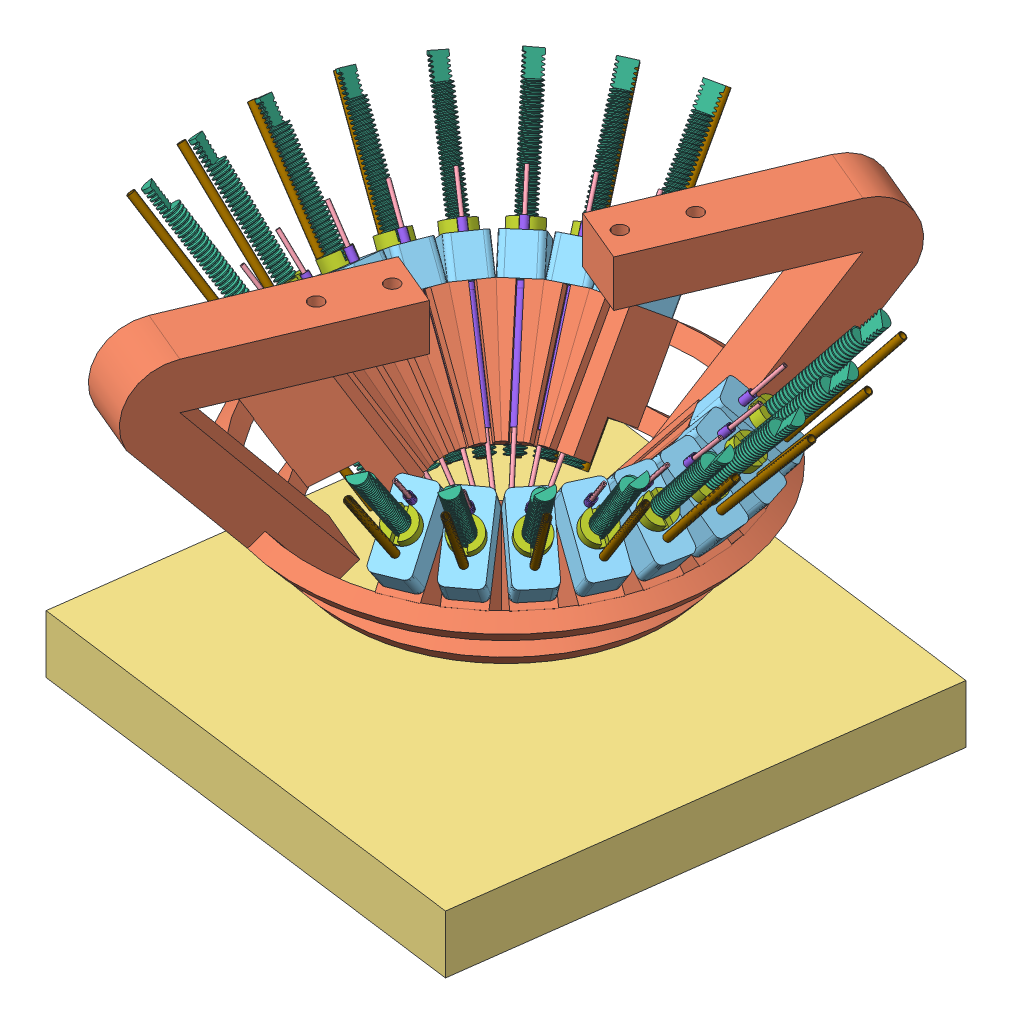
SolidWorks assembly DriveAssembling_Step4, configuration Default. Lengths in mm.
Overall size (53.46 35.24 53.46).
115 component instances, 9 part files, 84 mates.
Components (placement in the parent):
- MainCanula-1: MainCanula [Default] at (-0.6109 2 -0.3095) size (2.41 8 2.41)
- drive_circle_16-1: drive_circle_16 [Default] at (-0.6109 7.8932 -0.3095) x (0.377897 0 0.925848) z (-0.925848 0 0.377897) size (41.01 26.14 41.01)
- SingleCanulaBase-1: SingleCanulaBase [Default] at (-0.6109 0 -0.3095) x (0.991445 0 0.130526) z (-0.130526 0 0.991445) size (40 5 40)
- 30g_curved_long-18: 30g_curved_long [Default] at (-0.577 8 -0.2265) x (0.377897 0 0.925848) z (-0.925848 0 0.377897) size (17.44 28.79 0.32)
- ShuttleAssembly-1: ShuttleAssembly [Default] at (-0.0983 18.931 15.5592) x (-0.289486 0.642788 -0.70924) z (0.925848 0 -0.377897) size (6.5 25.22 3)
  - drive_shuttle-1: drive_shuttle [Default] at (2.5582 1.9761 5.5221) size (6.5 3 3)
  - drive_threaded_rod_25mm-1: drive_threaded_rod_25mm [Default] at (2.5582 -8.5786 5.5221) x (0.813094 0 0.582132) z (-0.582132 0 0.813094) size (1.64 25.22 1.64)
  - Grooved Nut-1: Grooved Nut [Default] at (2.5582 1.9761 5.5221) size (2.5 4 2.5)
  - guide_23g_13mm-1: guide_23g_13mm [Default] at (4.3082 -7.0239 5.5221) size (0.64 13 0.64)
  - stabilizer_23g_25mm-1: stabilizer_23g_25mm [Default] at (0.8082 -8.5786 5.5221) size (0.62 25 0.62)
- 30g_curved_long-23: 30g_curved_long [Default] at (-0.5576 8 -0.2375) x (0.594671 0 0.803969) z (-0.803969 0 0.594671) size (17.44 28.79 0.32)
- ShuttleAssembly-6: ShuttleAssembly [Default] at (3.8016 18.931 14.942) x (-0.455545 0.642788 -0.615876) z (0.803969 0 -0.594671) size (6.5 25.22 3)
  - drive_shuttle-1: drive_shuttle [Default] at (2.5582 1.9761 5.5221) size (6.5 3 3)
  - drive_threaded_rod_25mm-1: drive_threaded_rod_25mm [Default] at (2.5582 -8.5786 5.5221) x (0.813094 0 0.582132) z (-0.582132 0 0.813094) size (1.64 25.22 1.64)
  - Grooved Nut-1: Grooved Nut [Default] at (2.5582 1.9761 5.5221) size (2.5 4 2.5)
  - guide_23g_13mm-1: guide_23g_13mm [Default] at (4.3082 -7.0239 5.5221) size (0.64 13 0.64)
  - stabilizer_23g_25mm-1: stabilizer_23g_25mm [Default] at (0.8082 -8.5786 5.5221) size (0.62 25 0.62)
- 30g_curved_long-24: 30g_curved_long [Default] at (-0.5414 8 -0.2528) x (0.774668 0 0.632368) z (-0.632368 0 0.774668) size (17.44 28.79 0.32)
- ShuttleAssembly-7: ShuttleAssembly [Default] at (7.4286 18.931 13.3816) x (-0.59343 0.642788 -0.484422) z (0.632368 0 -0.774668) size (6.5 25.22 3)
  - drive_shuttle-1: drive_shuttle [Default] at (2.5582 1.9761 5.5221) size (6.5 3 3)
  - drive_threaded_rod_25mm-1: drive_threaded_rod_25mm [Default] at (2.5582 -8.5786 5.5221) x (0.813094 0 0.582132) z (-0.582132 0 0.813094) size (1.64 25.22 1.64)
  - Grooved Nut-1: Grooved Nut [Default] at (2.5582 1.9761 5.5221) size (2.5 4 2.5)
  - guide_23g_13mm-1: guide_23g_13mm [Default] at (4.3082 -7.0239 5.5221) size (0.64 13 0.64)
  - stabilizer_23g_25mm-1: stabilizer_23g_25mm [Default] at (0.8082 -8.5786 5.5221) size (0.62 25 0.62)
- 30g_curved_long-26: 30g_curved_long [Default] at (-0.5296 8 -0.2717) x (0.906755 0 0.421659) z (-0.421659 0 0.906755) size (17.44 28.79 0.32)
- ShuttleAssembly-9: ShuttleAssembly [Default] at (10.5584 18.931 10.9744) x (-0.694614 0.642788 -0.323009) z (0.421659 0 -0.906755) size (6.5 25.22 3)
  - drive_shuttle-1: drive_shuttle [Default] at (2.5582 1.9761 5.5221) size (6.5 3 3)
  - drive_threaded_rod_25mm-1: drive_threaded_rod_25mm [Default] at (2.5582 -8.5786 5.5221) x (0.813094 0 0.582132) z (-0.582132 0 0.813094) size (1.64 25.22 1.64)
  - Grooved Nut-1: Grooved Nut [Default] at (2.5582 1.9761 5.5221) size (2.5 4 2.5)
  - guide_23g_13mm-1: guide_23g_13mm [Default] at (4.3082 -7.0239 5.5221) size (0.64 13 0.64)
  - stabilizer_23g_25mm-1: stabilizer_23g_25mm [Default] at (0.8082 -8.5786 5.5221) size (0.62 25 0.62)
- 30g_curved_long-27: 30g_curved_long [Default] at (-0.5228 8 -0.293) x (0.982763 0 0.184872) z (-0.184872 0 0.982763) size (17.44 28.79 0.32)
- ShuttleAssembly-10: ShuttleAssembly [Default] at (12.9974 18.931 7.8694) x (-0.75284 0.642788 -0.14162) z (0.184872 0 -0.982763) size (6.5 25.22 3)
  - drive_shuttle-1: drive_shuttle [Default] at (2.5582 1.9761 5.5221) size (6.5 3 3)
  - drive_threaded_rod_25mm-1: drive_threaded_rod_25mm [Default] at (2.5582 -8.5786 5.5221) x (0.813094 0 0.582132) z (-0.582132 0 0.813094) size (1.64 25.22 1.64)
  - Grooved Nut-1: Grooved Nut [Default] at (2.5582 1.9761 5.5221) size (2.5 4 2.5)
  - guide_23g_13mm-1: guide_23g_13mm [Default] at (4.3082 -7.0239 5.5221) size (0.64 13 0.64)
  - stabilizer_23g_25mm-1: stabilizer_23g_25mm [Default] at (0.8082 -8.5786 5.5221) size (0.62 25 0.62)
- 30g_curved_long-28: 30g_curved_long [Default] at (-0.5214 8 -0.3152) x (0.997991 0 -0.063349) z (0.063349 0 0.997991) size (17.44 28.79 0.32)
- ShuttleAssembly-11: ShuttleAssembly [Default] at (14.5948 18.931 4.2585) x (-0.764506 0.642788 0.048528) z (-0.063349 0 -0.997991) size (6.5 25.22 3)
  - drive_shuttle-1: drive_shuttle [Default] at (2.5582 1.9761 5.5221) size (6.5 3 3)
  - drive_threaded_rod_25mm-1: drive_threaded_rod_25mm [Default] at (2.5582 -8.5786 5.5221) x (0.813094 0 0.582132) z (-0.582132 0 0.813094) size (1.64 25.22 1.64)
  - Grooved Nut-1: Grooved Nut [Default] at (2.5582 1.9761 5.5221) size (2.5 4 2.5)
  - guide_23g_13mm-1: guide_23g_13mm [Default] at (4.3082 -7.0239 5.5221) size (0.64 13 0.64)
  - stabilizer_23g_25mm-1: stabilizer_23g_25mm [Default] at (0.8082 -8.5786 5.5221) size (0.62 25 0.62)
- 30g_curved_long-29: 30g_curved_long [Default] at (-0.5256 8 -0.3371) x (0.951499 0 -0.307652) z (0.307652 0 0.951499) size (17.44 28.79 0.32)
- ShuttleAssembly-12: ShuttleAssembly [Default] at (15.2518 18.931 0.3651) x (-0.728891 0.642788 0.235675) z (-0.307652 0 -0.951499) size (6.5 25.22 3)
  - drive_shuttle-1: drive_shuttle [Default] at (2.5582 1.9761 5.5221) size (6.5 3 3)
  - drive_threaded_rod_25mm-1: drive_threaded_rod_25mm [Default] at (2.5582 -8.5786 5.5221) x (0.813094 0 0.582132) z (-0.582132 0 0.813094) size (1.64 25.22 1.64)
  - Grooved Nut-1: Grooved Nut [Default] at (2.5582 1.9761 5.5221) size (2.5 4 2.5)
  - guide_23g_13mm-1: guide_23g_13mm [Default] at (4.3082 -7.0239 5.5221) size (0.64 13 0.64)
  - stabilizer_23g_25mm-1: stabilizer_23g_25mm [Default] at (0.8082 -8.5786 5.5221) size (0.62 25 0.62)
- 30g_curved_long-30: 30g_curved_long [Default] at (-0.535 8 -0.3573) x (0.846161 0 -0.532928) z (0.532928 0 0.846161) size (17.44 28.79 0.32)
- ShuttleAssembly-13: ShuttleAssembly [Default] at (14.9278 18.931 -3.5699) x (-0.648197 0.642788 0.408246) z (-0.532928 0 -0.846161) size (6.5 25.22 3)
  - drive_shuttle-1: drive_shuttle [Default] at (2.5582 1.9761 5.5221) size (6.5 3 3)
  - drive_threaded_rod_25mm-1: drive_threaded_rod_25mm [Default] at (2.5582 -8.5786 5.5221) x (0.813094 0 0.582132) z (-0.582132 0 0.813094) size (1.64 25.22 1.64)
  - Grooved Nut-1: Grooved Nut [Default] at (2.5582 1.9761 5.5221) size (2.5 4 2.5)
  - guide_23g_13mm-1: guide_23g_13mm [Default] at (4.3082 -7.0239 5.5221) size (0.64 13 0.64)
  - stabilizer_23g_25mm-1: stabilizer_23g_25mm [Default] at (0.8082 -8.5786 5.5221) size (0.62 25 0.62)
- 30g_curved_long-42: 30g_curved_long [Default] at (-0.6298 8 -0.3972) x (-0.211384 0 -0.977403) z (0.977403 0 -0.211384) size (17.44 28.79 0.32)
- ShuttleAssembly-25: ShuttleAssembly [Default] at (1.6399 18.931 -16.0262) x (0.16193 0.642788 0.748734) z (-0.977403 0 0.211384) size (6.5 25.22 3)
  - drive_shuttle-1: drive_shuttle [Default] at (2.5582 1.9761 5.5221) size (6.5 3 3)
  - drive_threaded_rod_25mm-1: drive_threaded_rod_25mm [Default] at (2.5582 -8.5786 5.5221) x (0.813094 0 0.582132) z (-0.582132 0 0.813094) size (1.64 25.22 1.64)
  - Grooved Nut-1: Grooved Nut [Default] at (2.5582 1.9761 5.5221) size (2.5 4 2.5)
  - guide_23g_13mm-1: guide_23g_13mm [Default] at (4.3082 -7.0239 5.5221) size (0.64 13 0.64)
  - stabilizer_23g_25mm-1: stabilizer_23g_25mm [Default] at (0.8082 -8.5786 5.5221) size (0.62 25 0.62)
- 30g_curved_long-43: 30g_curved_long [Default] at (-0.6509 8 -0.3898) x (-0.446029 0 -0.895018) z (0.895018 0 -0.446029) size (17.44 28.79 0.32)
- ShuttleAssembly-26: ShuttleAssembly [Default] at (-2.3079 18.931 -16.0956) x (0.341678 0.642788 0.685624) z (-0.895018 0 0.446029) size (6.5 25.22 3)
  - drive_shuttle-1: drive_shuttle [Default] at (2.5582 1.9761 5.5221) size (6.5 3 3)
  - drive_threaded_rod_25mm-1: drive_threaded_rod_25mm [Default] at (2.5582 -8.5786 5.5221) x (0.813094 0 0.582132) z (-0.582132 0 0.813094) size (1.64 25.22 1.64)
  - Grooved Nut-1: Grooved Nut [Default] at (2.5582 1.9761 5.5221) size (2.5 4 2.5)
  - guide_23g_13mm-1: guide_23g_13mm [Default] at (4.3082 -7.0239 5.5221) size (0.64 13 0.64)
  - stabilizer_23g_25mm-1: stabilizer_23g_25mm [Default] at (0.8082 -8.5786 5.5221) size (0.62 25 0.62)
- 30g_curved_long-44: 30g_curved_long [Default] at (-0.6694 8 -0.3774) x (-0.653089 0 -0.757281) z (0.757281 0 -0.653089) size (17.44 28.79 0.32)
- ShuttleAssembly-27: ShuttleAssembly [Default] at (-6.1508 18.931 -15.1887) x (0.500295 0.642788 0.580111) z (-0.757281 0 0.653089) size (6.5 25.22 3)
  - drive_shuttle-1: drive_shuttle [Default] at (2.5582 1.9761 5.5221) size (6.5 3 3)
  - drive_threaded_rod_25mm-1: drive_threaded_rod_25mm [Default] at (2.5582 -8.5786 5.5221) x (0.813094 0 0.582132) z (-0.582132 0 0.813094) size (1.64 25.22 1.64)
  - Grooved Nut-1: Grooved Nut [Default] at (2.5582 1.9761 5.5221) size (2.5 4 2.5)
  - guide_23g_13mm-1: guide_23g_13mm [Default] at (4.3082 -7.0239 5.5221) size (0.64 13 0.64)
  - stabilizer_23g_25mm-1: stabilizer_23g_25mm [Default] at (0.8082 -8.5786 5.5221) size (0.62 25 0.62)
- 30g_curved_long-45: 30g_curved_long [Default] at (-0.6844 8 -0.3609) x (-0.819759 0 -0.572709) z (0.572709 0 -0.819759) size (17.44 28.79 0.32)
- ShuttleAssembly-28: ShuttleAssembly [Default] at (-9.651 18.931 -13.3616) x (0.627971 0.642788 0.438721) z (-0.572709 0 0.819759) size (6.5 25.22 3)
  - drive_shuttle-1: drive_shuttle [Default] at (2.5582 1.9761 5.5221) size (6.5 3 3)
  - drive_threaded_rod_25mm-1: drive_threaded_rod_25mm [Default] at (2.5582 -8.5786 5.5221) x (0.813094 0 0.582132) z (-0.582132 0 0.813094) size (1.64 25.22 1.64)
  - Grooved Nut-1: Grooved Nut [Default] at (2.5582 1.9761 5.5221) size (2.5 4 2.5)
  - guide_23g_13mm-1: guide_23g_13mm [Default] at (4.3082 -7.0239 5.5221) size (0.64 13 0.64)
  - stabilizer_23g_25mm-1: stabilizer_23g_25mm [Default] at (0.8082 -8.5786 5.5221) size (0.62 25 0.62)
- 30g_curved_long-49: 30g_curved_long [Default] at (-0.6948 8 -0.3412) x (-0.93573 0 -0.352718) z (0.352718 0 -0.93573) size (17.44 28.79 0.32)
- ShuttleAssembly-32: ShuttleAssembly [Default] at (-12.5922 18.931 -10.7272) x (0.716811 0.642788 0.270198) z (-0.352718 0 0.93573) size (6.5 25.22 3)
  - drive_shuttle-1: drive_shuttle [Default] at (2.5582 1.9761 5.5221) size (6.5 3 3)
  - drive_threaded_rod_25mm-1: drive_threaded_rod_25mm [Default] at (2.5582 -8.5786 5.5221) x (0.813094 0 0.582132) z (-0.582132 0 0.813094) size (1.64 25.22 1.64)
  - Grooved Nut-1: Grooved Nut [Default] at (2.5582 1.9761 5.5221) size (2.5 4 2.5)
  - guide_23g_13mm-1: guide_23g_13mm [Default] at (4.3082 -7.0239 5.5221) size (0.64 13 0.64)
  - stabilizer_23g_25mm-1: stabilizer_23g_25mm [Default] at (0.8082 -8.5786 5.5221) size (0.62 25 0.62)
- 30g_curved_long-50: 30g_curved_long [Default] at (-0.7 8 -0.3195) x (-0.99383 0 -0.110913) z (0.110913 0 -0.99383) size (17.44 28.79 0.32)
- ShuttleAssembly-33: ShuttleAssembly [Default] at (-14.7923 18.931 -7.4486) x (0.761318 0.642788 0.084964) z (-0.110913 0 0.99383) size (6.5 25.22 3)
  - drive_shuttle-1: drive_shuttle [Default] at (2.5582 1.9761 5.5221) size (6.5 3 3)
  - drive_threaded_rod_25mm-1: drive_threaded_rod_25mm [Default] at (2.5582 -8.5786 5.5221) x (0.813094 0 0.582132) z (-0.582132 0 0.813094) size (1.64 25.22 1.64)
  - Grooved Nut-1: Grooved Nut [Default] at (2.5582 1.9761 5.5221) size (2.5 4 2.5)
  - guide_23g_13mm-1: guide_23g_13mm [Default] at (4.3082 -7.0239 5.5221) size (0.64 13 0.64)
  - stabilizer_23g_25mm-1: stabilizer_23g_25mm [Default] at (0.8082 -8.5786 5.5221) size (0.62 25 0.62)
- 30g_curved_long-51: 30g_curved_long [Default] at (-0.6997 8 -0.2972) x (-0.990467 0 0.137752) z (-0.137752 0 -0.990467) size (17.44 28.79 0.32)
- ShuttleAssembly-34: ShuttleAssembly [Default] at (-16.1154 18.931 -3.7285) x (0.758742 0.642788 -0.105524) z (0.137752 0 0.990467) size (6.5 25.22 3)
  - drive_shuttle-1: drive_shuttle [Default] at (2.5582 1.9761 5.5221) size (6.5 3 3)
  - drive_threaded_rod_25mm-1: drive_threaded_rod_25mm [Default] at (2.5582 -8.5786 5.5221) x (0.813094 0 0.582132) z (-0.582132 0 0.813094) size (1.64 25.22 1.64)
  - Grooved Nut-1: Grooved Nut [Default] at (2.5582 1.9761 5.5221) size (2.5 4 2.5)
  - guide_23g_13mm-1: guide_23g_13mm [Default] at (4.3082 -7.0239 5.5221) size (0.64 13 0.64)
  - stabilizer_23g_25mm-1: stabilizer_23g_25mm [Default] at (0.8082 -8.5786 5.5221) size (0.62 25 0.62)
- 30g_curved_long-52: 30g_curved_long [Default] at (-0.6939 8 -0.2757) x (-0.925848 0 0.377897) z (-0.377897 0 -0.925848) size (17.44 28.79 0.32)
- ShuttleAssembly-35: ShuttleAssembly [Default] at (-16.4796 18.931 0.2031) x (0.70924 0.642788 -0.289486) z (0.377897 0 0.925848) size (6.5 25.22 3)
  - drive_shuttle-1: drive_shuttle [Default] at (2.5582 1.9761 5.5221) size (6.5 3 3)
  - drive_threaded_rod_25mm-1: drive_threaded_rod_25mm [Default] at (2.5582 -8.5786 5.5221) x (0.813094 0 0.582132) z (-0.582132 0 0.813094) size (1.64 25.22 1.64)
  - Grooved Nut-1: Grooved Nut [Default] at (2.5582 1.9761 5.5221) size (2.5 4 2.5)
  - guide_23g_13mm-1: guide_23g_13mm [Default] at (4.3082 -7.0239 5.5221) size (0.64 13 0.64)
  - stabilizer_23g_25mm-1: stabilizer_23g_25mm [Default] at (0.8082 -8.5786 5.5221) size (0.62 25 0.62)
Mates (geometry in assembly coordinates):
- Concentric3: concentric aligned: circle of MainCanula-1; circle of SingleCanulaBase-1
- Coincident3: coincident aligned: plane of MainCanula-1 through (-0.6109 0 -0.3095) normal (0 -1 0); plane of SingleCanulaBase-1 through (-0.6109 0 -0.3095) normal (0 -1 0)
- Coincident6-30g, bottom: coincident anti-aligned: plane of 30g_curved_long-18 through (-0.5014 0 -0.0414) normal (0 -1 0); plane of assembly through (0 0 0) normal (0 1 0)
- Concentric6-guidetube: concentric aligned: circle of drive_circle_16-1; circle of 30g_curved_long-18
- Concentric7-stabilizer: concentric aligned: circle of drive_circle_16-1; circle of ShuttleAssembly-1/stabilizer_23g_25mm-1
- Concentric8-30g: concentric aligned: circle of 30g_curved_long-18; circle of ShuttleAssembly-1/guide_23g_13mm-1
- Coincident10 - FlushShuttle: coincident anti-aligned: plane of drive_circle_16-1 through (5.2018 24.1782 9.9622) normal (0.242908 0.766044 0.595123); plane of ShuttleAssembly-1/drive_shuttle-1 through (4.7539 22.0892 12.8341) normal (-0.242908 -0.766044 -0.595123)
- Concentric9: concentric anti-aligned: circle of MainCanula-1; circle of drive_circle_16-1
- Concentric20: concentric aligned: circle of 30g_curved_long-23; circle of ShuttleAssembly-6/guide_23g_13mm-1
- Coincident10: coincident anti-aligned: plane of 30g_curved_long-23 through (-0.4386 0 -0.0767) normal (0 -1 0); plane of assembly through (0 0 0) normal (0 1 0)
- Concentric21: concentric aligned: circle of drive_circle_16-1; circle of 30g_curved_long-23
- Concentric22: concentric aligned: circle of drive_circle_16-1; circle of ShuttleAssembly-6/stabilizer_23g_25mm-1
- Coincident11: coincident anti-aligned: plane of drive_circle_16-1 through (7.5567 24.1782 8.2103) normal (0.382247 0.766044 0.516781); plane of ShuttleAssembly-6/drive_shuttle-1 through (7.8313 22.0892 11.1039) normal (-0.382247 -0.766044 -0.516781)
- Concentric23: concentric aligned: circle of 30g_curved_long-24; circle of ShuttleAssembly-7/guide_23g_13mm-1
- Coincident12: coincident anti-aligned: plane of 30g_curved_long-24 through (-0.3865 0 -0.1264) normal (0 -1 0); plane of assembly through (0 0 0) normal (0 1 0)
- Concentric24: concentric aligned: circle of drive_circle_16-1; circle of 30g_curved_long-24
- Concentric25: concentric aligned: circle of drive_circle_16-1; circle of ShuttleAssembly-7/stabilizer_23g_25mm-1
- Coincident13: coincident anti-aligned: plane of drive_circle_16-1 through (9.4065 24.1782 5.9314) normal (0.497947 0.766044 0.406479); plane of ShuttleAssembly-7/drive_shuttle-1 through (10.3866 22.0892 8.6678) normal (-0.497947 -0.766044 -0.406479)
- Concentric29: concentric aligned: circle of 30g_curved_long-26; circle of ShuttleAssembly-9/guide_23g_13mm-1
- Coincident16: coincident anti-aligned: plane of 30g_curved_long-26 through (-0.3482 0 -0.1874) normal (0 -1 0); plane of assembly through (0 0 0) normal (0 1 0)
- Concentric30: concentric aligned: circle of drive_circle_16-1; circle of 30g_curved_long-26
- Concentric31: concentric aligned: circle of drive_circle_16-1; circle of ShuttleAssembly-9/stabilizer_23g_25mm-1
- Coincident17: coincident anti-aligned: plane of drive_circle_16-1 through (10.6367 24.1782 3.2666) normal (0.582851 0.766044 0.271037); plane of ShuttleAssembly-9/drive_shuttle-1 through (12.2617 22.0892 5.6765) normal (-0.582851 -0.766044 -0.271037)
- Concentric32: concentric aligned: circle of 30g_curved_long-27; circle of ShuttleAssembly-10/guide_23g_13mm-1
- Coincident18: coincident anti-aligned: plane of 30g_curved_long-27 through (-0.3262 0 -0.256) normal (0 -1 0); plane of assembly through (0 0 0) normal (0 1 0)
- Concentric33: concentric aligned: circle of drive_circle_16-1; circle of 30g_curved_long-27
- Concentric34: concentric aligned: circle of drive_circle_16-1; circle of ShuttleAssembly-10/stabilizer_23g_25mm-1
- Coincident20: coincident anti-aligned: plane of drive_circle_16-1 through (11.1713 24.1782 0.3806) normal (0.631708 0.766044 0.118833); plane of ShuttleAssembly-10/drive_shuttle-1 through (13.3407 22.0892 2.315) normal (-0.631708 -0.766044 -0.118833)
- Concentric35: concentric aligned: circle of 30g_curved_long-28; circle of ShuttleAssembly-11/guide_23g_13mm-1
- Coincident21: coincident anti-aligned: plane of 30g_curved_long-28 through (-0.3218 0 -0.3279) normal (0 -1 0); plane of assembly through (0 0 0) normal (0 1 0)
- Concentric36: concentric aligned: circle of drive_circle_16-1; circle of 30g_curved_long-28
- Concentric37: concentric aligned: circle of drive_circle_16-1; circle of ShuttleAssembly-11/stabilizer_23g_25mm-1
- Coincident22: coincident anti-aligned: plane of drive_circle_16-1 through (10.9773 24.1782 -2.5481) normal (0.641497 0.766044 -0.04072); plane of ShuttleAssembly-11/drive_shuttle-1 through (13.5569 22.0892 -1.2089) normal (-0.641497 -0.766044 0.04072)
- Concentric38: concentric aligned: circle of 30g_curved_long-29; circle of ShuttleAssembly-12/guide_23g_13mm-1
- Coincident23: coincident anti-aligned: plane of 30g_curved_long-29 through (-0.3353 0 -0.3986) normal (0 -1 0); plane of assembly through (0 0 0) normal (0 1 0)
- Concentric39: concentric aligned: circle of drive_circle_16-1; circle of 30g_curved_long-29
- Concentric40: concentric aligned: circle of drive_circle_16-1; circle of ShuttleAssembly-12/stabilizer_23g_25mm-1
- Coincident24: coincident anti-aligned: plane of drive_circle_16-1 through (10.0665 24.1782 -5.3384) normal (0.611612 0.766044 -0.197755); plane of ShuttleAssembly-12/drive_shuttle-1 through (12.8969 22.0892 -4.6771) normal (-0.611612 -0.766044 0.197755)
- Concentric41: concentric aligned: circle of 30g_curved_long-30; circle of ShuttleAssembly-13/guide_23g_13mm-1
- Coincident25: coincident anti-aligned: plane of 30g_curved_long-30 through (-0.3658 0 -0.4639) normal (0 -1 0); plane of assembly through (0 0 0) normal (0 1 0)
- Concentric42: concentric aligned: circle of drive_circle_16-1; circle of 30g_curved_long-30
- Concentric43: concentric aligned: circle of drive_circle_16-1; circle of ShuttleAssembly-13/stabilizer_23g_25mm-1
- Coincident27: coincident anti-aligned: plane of drive_circle_16-1 through (8.4955 24.1782 -7.8176) normal (0.543902 0.766044 -0.342559); plane of ShuttleAssembly-13/drive_shuttle-1 through (11.4015 22.0892 -7.8752) normal (-0.543902 -0.766044 0.342559)
- Concentric66: concentric anti-aligned: circle of 30g_curved_long-42; circle of drive_circle_16-1
- Coincident41: coincident anti-aligned: plane of assembly through (0 0 0) normal (0 1 0); plane of 30g_curved_long-42 through (-0.6721 0 -0.5926) normal (0 -1 0)
- Concentric67: concentric aligned: circle of 30g_curved_long-42; circle of ShuttleAssembly-25/guide_23g_13mm-1
- Concentric68: concentric anti-aligned: circle of drive_circle_16-1; circle of ShuttleAssembly-25/stabilizer_23g_25mm-1
- Coincident42: coincident anti-aligned: plane of drive_circle_16-1 through (-1.6194 24.1782 -12.0688) normal (-0.135875 0.766044 -0.628263); plane of ShuttleAssembly-25/drive_shuttle-1 through (-3.6118 22.0892 -14.1851) normal (0.135875 -0.766044 0.628263)
- Concentric69: concentric aligned: circle of 30g_curved_long-43; circle of ShuttleAssembly-26/guide_23g_13mm-1
- Concentric70: concentric anti-aligned: circle of drive_circle_16-1; circle of 30g_curved_long-43
- Coincident43: coincident anti-aligned: plane of 30g_curved_long-43 through (-0.7401 0 -0.5688) normal (0 -1 0); plane of assembly through (0 0 0) normal (0 1 0)
- Concentric71: concentric anti-aligned: circle of drive_circle_16-1; circle of ShuttleAssembly-26/stabilizer_23g_25mm-1
- Coincident44: coincident anti-aligned: plane of drive_circle_16-1 through (-4.4899 24.1782 -11.4563) normal (-0.286702 0.766044 -0.575307); plane of ShuttleAssembly-26/drive_shuttle-1 through (-6.9429 22.0892 -13.0155) normal (0.286702 -0.766044 0.575307)
- Concentric72: concentric aligned: circle of 30g_curved_long-44; circle of ShuttleAssembly-27/guide_23g_13mm-1
- Concentric73: concentric anti-aligned: circle of drive_circle_16-1; circle of 30g_curved_long-44
- Coincident45: coincident anti-aligned: plane of assembly through (0 0 0) normal (0 1 0); plane of 30g_curved_long-44 through (-0.8 0 -0.5289) normal (0 -1 0)
- Concentric74: concentric anti-aligned: circle of drive_circle_16-1; circle of ShuttleAssembly-27/stabilizer_23g_25mm-1
- Coincident46: coincident anti-aligned: plane of drive_circle_16-1 through (-7.1205 24.1782 -10.1544) normal (-0.419798 0.766044 -0.486771); plane of ShuttleAssembly-27/drive_shuttle-1 through (-9.8824 22.0892 -11.0601) normal (0.419798 -0.766044 0.486771)
- Concentric75: concentric aligned: circle of 30g_curved_long-45; circle of ShuttleAssembly-28/guide_23g_13mm-1
- Concentric76: concentric anti-aligned: circle of drive_circle_16-1; circle of 30g_curved_long-45
- Coincident47: coincident anti-aligned: plane of assembly through (0 0 0) normal (0 1 0); plane of 30g_curved_long-45 through (-0.8483 0 -0.4754) normal (0 -1 0)
- Concentric77: concentric anti-aligned: circle of drive_circle_16-1; circle of ShuttleAssembly-28/stabilizer_23g_25mm-1
- Coincident48: coincident anti-aligned: plane of drive_circle_16-1 through (-9.3485 24.1782 -8.2437) normal (-0.526931 0.766044 -0.36813); plane of ShuttleAssembly-28/drive_shuttle-1 through (-12.2484 22.0892 -8.4399) normal (0.526931 -0.766044 0.36813)
- Coincident49: coincident anti-aligned: plane of assembly through (0 0 0) normal (0 1 0); plane of 30g_curved_long-43 through (-0.7401 0 -0.5688) normal (0 -1 0)
- Concentric82: concentric aligned: circle of 30g_curved_long-49; circle of ShuttleAssembly-32/guide_23g_13mm-1
- Concentric83: concentric anti-aligned: circle of drive_circle_16-1; circle of 30g_curved_long-49
- Coincident54: coincident aligned: plane of 30g_curved_long-43 through (-0.7401 0 -0.5688) normal (0 -1 0); plane of 30g_curved_long-49 through (-0.8819 0 -0.4117) normal (0 -1 0)
- Concentric84: concentric anti-aligned: circle of drive_circle_16-1; circle of ShuttleAssembly-32/stabilizer_23g_25mm-1
- Coincident55: coincident anti-aligned: plane of drive_circle_16-1 through (-11.0361 24.1782 -5.8423) normal (-0.601475 0.766044 -0.226723); plane of ShuttleAssembly-32/drive_shuttle-1 through (-13.8948 22.0892 -5.3168) normal (0.601475 -0.766044 0.226723)
- Concentric85: concentric aligned: circle of 30g_curved_long-50; circle of ShuttleAssembly-33/guide_23g_13mm-1
- Concentric86: concentric anti-aligned: circle of drive_circle_16-1; circle of 30g_curved_long-50
- Coincident56: coincident aligned: plane of 30g_curved_long-43 through (-0.7401 0 -0.5688) normal (0 -1 0); plane of 30g_curved_long-50 through (-0.8987 0 -0.3417) normal (0 -1 0)
- Concentric87: concentric anti-aligned: circle of drive_circle_16-1; circle of ShuttleAssembly-33/stabilizer_23g_25mm-1
- Coincident57: coincident anti-aligned: plane of drive_circle_16-1 through (-12.079 24.1782 -3.0987) normal (-0.638822 0.766044 -0.071293); plane of ShuttleAssembly-33/drive_shuttle-1 through (-14.7196 22.0892 -1.8841) normal (0.638822 -0.766044 0.071293)
- Concentric88: concentric aligned: circle of 30g_curved_long-51; circle of ShuttleAssembly-34/guide_23g_13mm-1
- Concentric89: concentric anti-aligned: circle of drive_circle_16-1; circle of 30g_curved_long-51
- Coincident58: coincident aligned: plane of 30g_curved_long-43 through (-0.7401 0 -0.5688) normal (0 -1 0); plane of 30g_curved_long-51 through (-0.8978 0 -0.2696) normal (0 -1 0)
- Concentric90: concentric anti-aligned: circle of drive_circle_16-1; circle of ShuttleAssembly-34/stabilizer_23g_25mm-1
- Coincident59: coincident anti-aligned: plane of drive_circle_16-1 through (-12.4126 24.1782 -0.1826) normal (-0.63666 0.766044 0.088545); plane of ShuttleAssembly-34/drive_shuttle-1 through (-14.6719 22.0892 1.646) normal (0.63666 -0.766044 -0.088545)
- Concentric91: concentric aligned: circle of 30g_curved_long-52; circle of ShuttleAssembly-35/guide_23g_13mm-1
- Concentric92: concentric anti-aligned: circle of drive_circle_16-1; circle of 30g_curved_long-52
- Coincident60: coincident aligned: plane of 30g_curved_long-43 through (-0.7401 0 -0.5688) normal (0 -1 0); plane of 30g_curved_long-52 through (-0.8791 0 -0.2001) normal (0 -1 0)
- Concentric93: concentric anti-aligned: circle of drive_circle_16-1; circle of ShuttleAssembly-35/stabilizer_23g_25mm-1
- Coincident61: coincident anti-aligned: plane of drive_circle_16-1 through (-12.0163 24.1782 2.7256) normal (-0.595123 0.766044 0.242908); plane of ShuttleAssembly-35/drive_shuttle-1 through (-13.7545 22.0892 5.0552) normal (0.595123 -0.766044 -0.242908)
